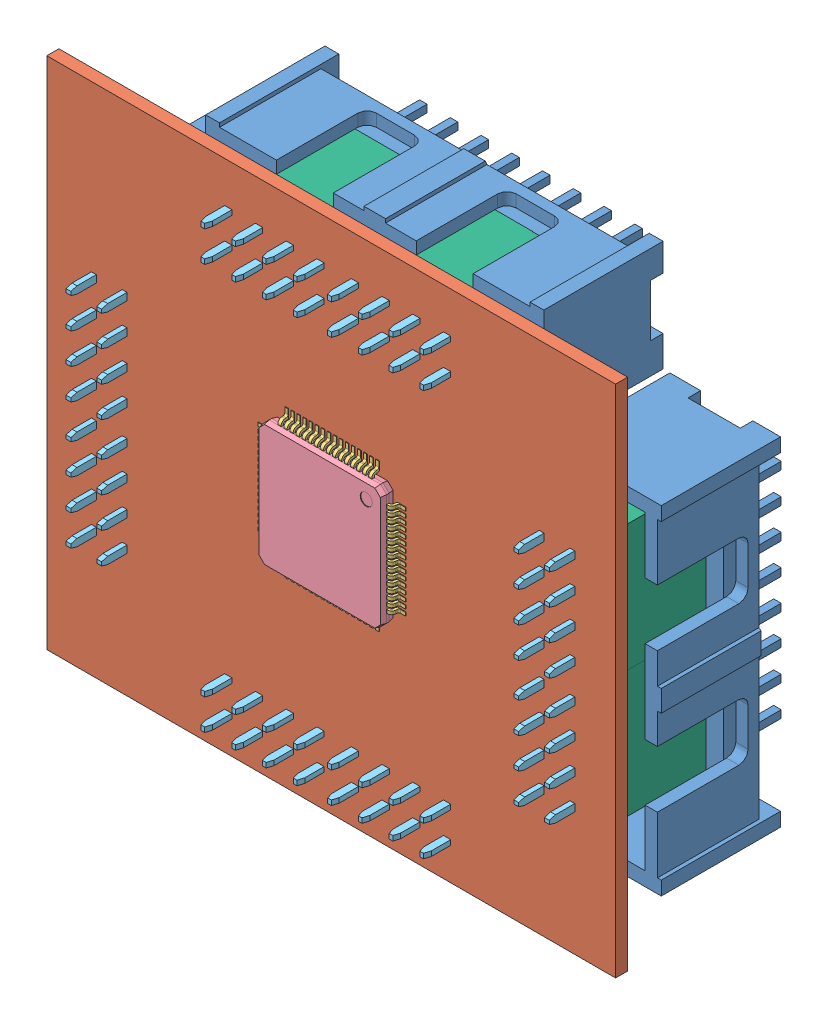
SolidWorks assembly Pic32Board-Chip-And-Support, configuration Défaut. Lengths in mm.
Overall size (47.77 43.45 18).
157 component instances, 6 part files, 4 mates.
Components (placement in the parent):
- Pic32Board-Support-1: Pic32Board-Support [Défaut] at (-7.1576 -16.2986 18.8481) size (46.79 42.79 12.9)
  - HE10-16Way-1: HE10-16Way [Default] at (-6.8205 -0.3878 34.3917) size (27.94 9.14 12.9)
  - HE10-16Way-3: HE10-16Way [Default] at (-6.8205 33.2562 34.3917) x (-1 0 0) z (0 0 1) size (27.94 9.14 12.9)
  - HE10-16Way-4: HE10-16Way [Default] at (12.2815 14.7142 34.3917) x (0 1 0) z (0 0 1) size (27.94 9.14 12.9)
  - HE10-16Way-5: HE10-16Way [Default] at (-25.3625 14.7142 34.3917) x (0 -1 0) z (0 0 1) size (27.94 9.14 12.9)
- Pic32Board-1: Pic32Board [Défaut] at (-20.8201 0.0031 8.7398) x (-1 0 0) z (0 0 1) size (47 42.5 11.6)
  - Pic32Board-1: Pic32Board [Défaut] at (-29.7416 -22.193 46.5) size (47 42.5 1)
  - User Library-TQFP64-2-1: User Library-TQFP64-2 [Default] at (-6.3416 -0.843 48.025) x (1 0 0) z (0 -1 0) size (12.2 1.2 12.2)
    - User Library-TQFP64-2_Leg x0-27 y0-575 z1-0-1: User Library-TQFP64-2_Leg x0-27 y0-575 z1-0 [Default] at (-5.1 0 -1.25) x (0 0 1) z (-1 0 0) size (0.27 0.78 1)
    - User Library-TQFP64-2_Leg x0-27 y0-575 z1-0-2: User Library-TQFP64-2_Leg x0-27 y0-575 z1-0 [Default] at (-2.75 0 -5.1001) x (-1 0 0) z (0 0 -1) size (0.27 0.78 1)
    - User Library-TQFP64-2_Leg x0-27 y0-575 z1-0-3: User Library-TQFP64-2_Leg x0-27 y0-575 z1-0 [Default] at (-5.1 0 2.25) x (0 0 1) z (-1 0 0) size (0.27 0.78 1)
    - User Library-TQFP64-2_Leg x0-27 y0-575 z1-0-4: User Library-TQFP64-2_Leg x0-27 y0-575 z1-0 [Default] at (5.1 0 -3.25) x (0 0 -1) z (1 0 0) size (0.27 0.78 1)
    - User Library-TQFP64-2_Leg x0-27 y0-575 z1-0-5: User Library-TQFP64-2_Leg x0-27 y0-575 z1-0 [Default] at (-1.25 0 5.1001) size (0.27 0.78 1)
    - User Library-TQFP64-2_Leg x0-27 y0-575 z1-0-6: User Library-TQFP64-2_Leg x0-27 y0-575 z1-0 [Default] at (2.75 0 5.1001) size (0.27 0.78 1)
    - User Library-TQFP64-2_Leg x0-27 y0-575 z1-0-7: User Library-TQFP64-2_Leg x0-27 y0-575 z1-0 [Default] at (2.25 0 5.1001) size (0.27 0.78 1)
    - User Library-TQFP64-2_Leg x0-27 y0-575 z1-0-8: User Library-TQFP64-2_Leg x0-27 y0-575 z1-0 [Default] at (5.1 0 -0.25) x (0 0 -1) z (1 0 0) size (0.27 0.78 1)
    - User Library-TQFP64-2_Leg x0-27 y0-575 z1-0-9: User Library-TQFP64-2_Leg x0-27 y0-575 z1-0 [Default] at (-5.1 0 -0.75) x (0 0 1) z (-1 0 0) size (0.27 0.78 1)
    - User Library-TQFP64-2_Leg x0-27 y0-575 z1-0-10: User Library-TQFP64-2_Leg x0-27 y0-575 z1-0 [Default] at (2.25 0 -5.1001) x (-1 0 0) z (0 0 -1) size (0.27 0.78 1)
    - User Library-TQFP64-2_Leg x0-27 y0-575 z1-0-11: User Library-TQFP64-2_Leg x0-27 y0-575 z1-0 [Default] at (5.1 0 0.75) x (0 0 -1) z (1 0 0) size (0.27 0.78 1)
    - User Library-TQFP64-2_Leg x0-27 y0-575 z1-0-12: User Library-TQFP64-2_Leg x0-27 y0-575 z1-0 [Default] at (-0.25 0 -5.1001) x (-1 0 0) z (0 0 -1) size (0.27 0.78 1)
    - User Library-TQFP64-2_Leg x0-27 y0-575 z1-0-13: User Library-TQFP64-2_Leg x0-27 y0-575 z1-0 [Default] at (5.1 0 0.25) x (0 0 -1) z (1 0 0) size (0.27 0.78 1)
    - User Library-TQFP64-2_Leg x0-27 y0-575 z1-0-14: User Library-TQFP64-2_Leg x0-27 y0-575 z1-0 [Default] at (1.75 0 5.1001) size (0.27 0.78 1)
    - User Library-TQFP64-2_Leg x0-27 y0-575 z1-0-15: User Library-TQFP64-2_Leg x0-27 y0-575 z1-0 [Default] at (-1.25 0 -5.1001) x (-1 0 0) z (0 0 -1) size (0.27 0.78 1)
    - User Library-TQFP64-2_Leg x0-27 y0-575 z1-0-16: User Library-TQFP64-2_Leg x0-27 y0-575 z1-0 [Default] at (-5.1 0 1.75) x (0 0 1) z (-1 0 0) size (0.27 0.78 1)
    - User Library-TQFP64-2_Leg x0-27 y0-575 z1-0-17: User Library-TQFP64-2_Leg x0-27 y0-575 z1-0 [Default] at (3.25 0 5.1001) size (0.27 0.78 1)
    - User Library-TQFP64-2_Leg x0-27 y0-575 z1-0-18: User Library-TQFP64-2_Leg x0-27 y0-575 z1-0 [Default] at (2.75 0 -5.1001) x (-1 0 0) z (0 0 -1) size (0.27 0.78 1)
    - User Library-TQFP64-2_Leg x0-27 y0-575 z1-0-19: User Library-TQFP64-2_Leg x0-27 y0-575 z1-0 [Default] at (5.1 0 2.25) x (0 0 -1) z (1 0 0) size (0.27 0.78 1)
    - User Library-TQFP64-2_Leg x0-27 y0-575 z1-0-20: User Library-TQFP64-2_Leg x0-27 y0-575 z1-0 [Default] at (-3.25 0 -5.1001) x (-1 0 0) z (0 0 -1) size (0.27 0.78 1)
    - User Library-TQFP64-2_Leg x0-27 y0-575 z1-0-21: User Library-TQFP64-2_Leg x0-27 y0-575 z1-0 [Default] at (-3.75 0 5.1001) size (0.27 0.78 1)
    - User Library-TQFP64-2_Leg x0-27 y0-575 z1-0-22: User Library-TQFP64-2_Leg x0-27 y0-575 z1-0 [Default] at (-3.25 0 5.1001) size (0.27 0.78 1)
    - User Library-TQFP64-2_Leg x0-27 y0-575 z1-0-23: User Library-TQFP64-2_Leg x0-27 y0-575 z1-0 [Default] at (3.75 0 5.1001) size (0.27 0.78 1)
    - User Library-TQFP64-2_Leg x0-27 y0-575 z1-0-24: User Library-TQFP64-2_Leg x0-27 y0-575 z1-0 [Default] at (-5.1 0 0.25) x (0 0 1) z (-1 0 0) size (0.27 0.78 1)
    - User Library-TQFP64-2_Leg x0-27 y0-575 z1-0-25: User Library-TQFP64-2_Leg x0-27 y0-575 z1-0 [Default] at (5.1 0 3.25) x (0 0 -1) z (1 0 0) size (0.27 0.78 1)
    - User Library-TQFP64-2_Leg x0-27 y0-575 z1-0-26: User Library-TQFP64-2_Leg x0-27 y0-575 z1-0 [Default] at (-5.1 0 0.75) x (0 0 1) z (-1 0 0) size (0.27 0.78 1)
    - User Library-TQFP64-2_Leg x0-27 y0-575 z1-0-27: User Library-TQFP64-2_Leg x0-27 y0-575 z1-0 [Default] at (0.75 0 -5.1001) x (-1 0 0) z (0 0 -1) size (0.27 0.78 1)
    - User Library-TQFP64-2_Leg x0-27 y0-575 z1-0-28: User Library-TQFP64-2_Leg x0-27 y0-575 z1-0 [Default] at (5.1 0 1.75) x (0 0 -1) z (1 0 0) size (0.27 0.78 1)
    - User Library-TQFP64-2_Leg x0-27 y0-575 z1-0-29: User Library-TQFP64-2_Leg x0-27 y0-575 z1-0 [Default] at (-5.1 0 -3.75) x (0 0 1) z (-1 0 0) size (0.27 0.78 1)
    - User Library-TQFP64-2_Leg x0-27 y0-575 z1-0-30: User Library-TQFP64-2_Leg x0-27 y0-575 z1-0 [Default] at (5.1 0 -0.75) x (0 0 -1) z (1 0 0) size (0.27 0.78 1)
    - User Library-TQFP64-2_Leg x0-27 y0-575 z1-0-31: User Library-TQFP64-2_Leg x0-27 y0-575 z1-0 [Default] at (5.1 0 3.75) x (0 0 -1) z (1 0 0) size (0.27 0.78 1)
    - User Library-TQFP64-2_Leg x0-27 y0-575 z1-0-32: User Library-TQFP64-2_Leg x0-27 y0-575 z1-0 [Default] at (-2.25 0 5.1001) size (0.27 0.78 1)
    - User Library-TQFP64-2_Leg x0-27 y0-575 z1-0-33: User Library-TQFP64-2_Leg x0-27 y0-575 z1-0 [Default] at (-5.1 0 -3.25) x (0 0 1) z (-1 0 0) size (0.27 0.78 1)
    - User Library-TQFP64-2_Leg x0-27 y0-575 z1-0-34: User Library-TQFP64-2_Leg x0-27 y0-575 z1-0 [Default] at (-5.1 0 2.75) x (0 0 1) z (-1 0 0) size (0.27 0.78 1)
    - User Library-TQFP64-2_Leg x0-27 y0-575 z1-0-35: User Library-TQFP64-2_Leg x0-27 y0-575 z1-0 [Default] at (-5.1 0 3.75) x (0 0 1) z (-1 0 0) size (0.27 0.78 1)
    - User Library-TQFP64-2_Leg x0-27 y0-575 z1-0-36: User Library-TQFP64-2_Leg x0-27 y0-575 z1-0 [Default] at (1.25 0 -5.1001) x (-1 0 0) z (0 0 -1) size (0.27 0.78 1)
    - User Library-TQFP64-2_Leg x0-27 y0-575 z1-0-37: User Library-TQFP64-2_Leg x0-27 y0-575 z1-0 [Default] at (1.25 0 5.1001) size (0.27 0.78 1)
    - User Library-TQFP64-2_Leg x0-27 y0-575 z1-0-38: User Library-TQFP64-2_Leg x0-27 y0-575 z1-0 [Default] at (5.1 0 1.25) x (0 0 -1) z (1 0 0) size (0.27 0.78 1)
    - User Library-TQFP64-2_Leg x0-27 y0-575 z1-0-39: User Library-TQFP64-2_Leg x0-27 y0-575 z1-0 [Default] at (0.75 0 5.1001) size (0.27 0.78 1)
    - User Library-TQFP64-2_Leg x0-27 y0-575 z1-0-40: User Library-TQFP64-2_Leg x0-27 y0-575 z1-0 [Default] at (3.25 0 -5.1001) x (-1 0 0) z (0 0 -1) size (0.27 0.78 1)
    - User Library-TQFP64-2_Leg x0-27 y0-575 z1-0-41: User Library-TQFP64-2_Leg x0-27 y0-575 z1-0 [Default] at (-2.75 0 5.1001) size (0.27 0.78 1)
    - User Library-TQFP64-2_Leg x0-27 y0-575 z1-0-42: User Library-TQFP64-2_Leg x0-27 y0-575 z1-0 [Default] at (3.75 0 -5.1001) x (-1 0 0) z (0 0 -1) size (0.27 0.78 1)
    - User Library-TQFP64-2_Leg x0-27 y0-575 z1-0-43: User Library-TQFP64-2_Leg x0-27 y0-575 z1-0 [Default] at (1.75 0 -5.1001) x (-1 0 0) z (0 0 -1) size (0.27 0.78 1)
    - User Library-TQFP64-2_Leg x0-27 y0-575 z1-0-44: User Library-TQFP64-2_Leg x0-27 y0-575 z1-0 [Default] at (-5.1 0 -2.75) x (0 0 1) z (-1 0 0) size (0.27 0.78 1)
    - User Library-TQFP64-2_Leg x0-27 y0-575 z1-0-45: User Library-TQFP64-2_Leg x0-27 y0-575 z1-0 [Default] at (5.1 0 -2.25) x (0 0 -1) z (1 0 0) size (0.27 0.78 1)
    - User Library-TQFP64-2_Leg x0-27 y0-575 z1-0-46: User Library-TQFP64-2_Leg x0-27 y0-575 z1-0 [Default] at (-2.25 0 -5.1001) x (-1 0 0) z (0 0 -1) size (0.27 0.78 1)
    - User Library-TQFP64-2_Leg x0-27 y0-575 z1-0-47: User Library-TQFP64-2_Leg x0-27 y0-575 z1-0 [Default] at (-5.1 0 1.25) x (0 0 1) z (-1 0 0) size (0.27 0.78 1)
    - User Library-TQFP64-2_Leg x0-27 y0-575 z1-0-48: User Library-TQFP64-2_Leg x0-27 y0-575 z1-0 [Default] at (5.1 0 -3.75) x (0 0 -1) z (1 0 0) size (0.27 0.78 1)
    - User Library-TQFP64-2_Leg x0-27 y0-575 z1-0-49: User Library-TQFP64-2_Leg x0-27 y0-575 z1-0 [Default] at (0.25 0 -5.1001) x (-1 0 0) z (0 0 -1) size (0.27 0.78 1)
    - User Library-TQFP64-2_Leg x0-27 y0-575 z1-0-50: User Library-TQFP64-2_Leg x0-27 y0-575 z1-0 [Default] at (-3.75 0 -5.1001) x (-1 0 0) z (0 0 -1) size (0.27 0.78 1)
    - User Library-TQFP64-2_Leg x0-27 y0-575 z1-0-51: User Library-TQFP64-2_Leg x0-27 y0-575 z1-0 [Default] at (-5.1 0 -0.25) x (0 0 1) z (-1 0 0) size (0.27 0.78 1)
    - User Library-TQFP64-2_Leg x0-27 y0-575 z1-0-52: User Library-TQFP64-2_Leg x0-27 y0-575 z1-0 [Default] at (-0.75 0 5.1001) size (0.27 0.78 1)
    - User Library-TQFP64-2_Leg x0-27 y0-575 z1-0-53: User Library-TQFP64-2_Leg x0-27 y0-575 z1-0 [Default] at (5.1 0 -1.75) x (0 0 -1) z (1 0 0) size (0.27 0.78 1)
    - User Library-TQFP64-2_Leg x0-27 y0-575 z1-0-54: User Library-TQFP64-2_Leg x0-27 y0-575 z1-0 [Default] at (-5.1 0 -2.25) x (0 0 1) z (-1 0 0) size (0.27 0.78 1)
    - User Library-TQFP64-2_Leg x0-27 y0-575 z1-0-55: User Library-TQFP64-2_Leg x0-27 y0-575 z1-0 [Default] at (-0.75 0 -5.1001) x (-1 0 0) z (0 0 -1) size (0.27 0.78 1)
    - User Library-TQFP64-2_Leg x0-27 y0-575 z1-0-56: User Library-TQFP64-2_Leg x0-27 y0-575 z1-0 [Default] at (-5.1 0 3.25) x (0 0 1) z (-1 0 0) size (0.27 0.78 1)
    - User Library-TQFP64-2_Body x10-2 y10-2 z1-05-1: User Library-TQFP64-2_Body x10-2 y10-2 z1-05 [Default] at origin size (10.2 1.05 10.2)
    - User Library-TQFP64-2_Leg x0-27 y0-575 z1-0-57: User Library-TQFP64-2_Leg x0-27 y0-575 z1-0 [Default] at (0.25 0 5.1001) size (0.27 0.78 1)
    - User Library-TQFP64-2_Leg x0-27 y0-575 z1-0-58: User Library-TQFP64-2_Leg x0-27 y0-575 z1-0 [Default] at (5.1 0 2.75) x (0 0 -1) z (1 0 0) size (0.27 0.78 1)
    - User Library-TQFP64-2_Leg x0-27 y0-575 z1-0-59: User Library-TQFP64-2_Leg x0-27 y0-575 z1-0 [Default] at (-1.75 0 -5.1001) x (-1 0 0) z (0 0 -1) size (0.27 0.78 1)
    - User Library-TQFP64-2_Leg x0-27 y0-575 z1-0-60: User Library-TQFP64-2_Leg x0-27 y0-575 z1-0 [Default] at (-5.1 0 -1.75) x (0 0 1) z (-1 0 0) size (0.27 0.78 1)
    - User Library-TQFP64-2_Leg x0-27 y0-575 z1-0-61: User Library-TQFP64-2_Leg x0-27 y0-575 z1-0 [Default] at (-0.25 0 5.1001) size (0.27 0.78 1)
    - User Library-TQFP64-2_Leg x0-27 y0-575 z1-0-62: User Library-TQFP64-2_Leg x0-27 y0-575 z1-0 [Default] at (-1.75 0 5.1001) size (0.27 0.78 1)
    - User Library-TQFP64-2_Leg x0-27 y0-575 z1-0-63: User Library-TQFP64-2_Leg x0-27 y0-575 z1-0 [Default] at (5.1 0 -2.75) x (0 0 -1) z (1 0 0) size (0.27 0.78 1)
    - User Library-TQFP64-2_Leg x0-27 y0-575 z1-0-64: User Library-TQFP64-2_Leg x0-27 y0-575 z1-0 [Default] at (5.1 0 -1.25) x (0 0 -1) z (1 0 0) size (0.27 0.78 1)
  - HE10-16Way-Female-1: HE10-16Way-Female [Défaut] at (-8.4334 -17.4128 55.4002) x (1 0 0) z (0 0 -1) size (20.92 5.68 11.6)
    - User Library-MULTICOMP 2214S-08SG-85-1: User Library-MULTICOMP 2214S-08SG-85 [Default] at (-3.5782 -0.0598 8.9002) size (10.46 5.68 11.6)
      - User Library-MULTICOMP 2214S-08SG-85_contact-1: User Library-MULTICOMP 2214S-08SG-85_contact [Default] at (-3.81 -1.07 0.9) x (1 0 0) z (0 -1 0) size (2 10 0.4)
      - User Library-MULTICOMP 2214S-08SG-85_contact-2: User Library-MULTICOMP 2214S-08SG-85_contact [Default] at (-3.81 1.47 0.9) x (1 0 0) z (0 -1 0) size (2 10 0.4)
      - User Library-MULTICOMP 2214S-08SG-85_contact-3: User Library-MULTICOMP 2214S-08SG-85_contact [Default] at (-1.27 -1.07 0.9) x (1 0 0) z (0 -1 0) size (2 10 0.4)
      - User Library-MULTICOMP 2214S-08SG-85_contact-4: User Library-MULTICOMP 2214S-08SG-85_contact [Default] at (-1.27 1.47 0.9) x (1 0 0) z (0 -1 0) size (2 10 0.4)
      - User Library-MULTICOMP 2214S-08SG-85_contact-5: User Library-MULTICOMP 2214S-08SG-85_contact [Default] at (1.27 1.47 0.9) x (1 0 0) z (0 -1 0) size (2 10 0.4)
      - User Library-MULTICOMP 2214S-08SG-85_contact-6: User Library-MULTICOMP 2214S-08SG-85_contact [Default] at (1.27 -1.07 0.9) x (1 0 0) z (0 -1 0) size (2 10 0.4)
      - User Library-MULTICOMP 2214S-08SG-85_contact-7: User Library-MULTICOMP 2214S-08SG-85_contact [Default] at (3.81 -1.47 0.9) x (-1 0 0) z (0 1 0) size (2 10 0.4)
      - User Library-MULTICOMP 2214S-08SG-85_contact-8: User Library-MULTICOMP 2214S-08SG-85_contact [Default] at (3.81 1.07 0.9) x (-1 0 0) z (0 1 0) size (2 10 0.4)
      - User Library-MULTICOMP 2214S-08SG-85_housing-1: User Library-MULTICOMP 2214S-08SG-85_housing [Default] at origin size (10.46 5.68 8.5)
    - User Library-MULTICOMP 2214S-08SG-85-2: User Library-MULTICOMP 2214S-08SG-85 [Default] at (6.8818 -0.0598 8.9002) size (10.46 5.68 11.6)
      - User Library-MULTICOMP 2214S-08SG-85_contact-1: User Library-MULTICOMP 2214S-08SG-85_contact [Default] at (-3.81 -1.07 0.9) x (1 0 0) z (0 -1 0) size (2 10 0.4)
      - User Library-MULTICOMP 2214S-08SG-85_contact-2: User Library-MULTICOMP 2214S-08SG-85_contact [Default] at (-3.81 1.47 0.9) x (1 0 0) z (0 -1 0) size (2 10 0.4)
      - User Library-MULTICOMP 2214S-08SG-85_contact-3: User Library-MULTICOMP 2214S-08SG-85_contact [Default] at (-1.27 -1.07 0.9) x (1 0 0) z (0 -1 0) size (2 10 0.4)
      - User Library-MULTICOMP 2214S-08SG-85_contact-4: User Library-MULTICOMP 2214S-08SG-85_contact [Default] at (-1.27 1.47 0.9) x (1 0 0) z (0 -1 0) size (2 10 0.4)
      - User Library-MULTICOMP 2214S-08SG-85_contact-5: User Library-MULTICOMP 2214S-08SG-85_contact [Default] at (1.27 1.47 0.9) x (1 0 0) z (0 -1 0) size (2 10 0.4)
      - User Library-MULTICOMP 2214S-08SG-85_contact-6: User Library-MULTICOMP 2214S-08SG-85_contact [Default] at (1.27 -1.07 0.9) x (1 0 0) z (0 -1 0) size (2 10 0.4)
      - User Library-MULTICOMP 2214S-08SG-85_contact-7: User Library-MULTICOMP 2214S-08SG-85_contact [Default] at (3.81 -1.47 0.9) x (-1 0 0) z (0 1 0) size (2 10 0.4)
      - User Library-MULTICOMP 2214S-08SG-85_contact-8: User Library-MULTICOMP 2214S-08SG-85_contact [Default] at (3.81 1.07 0.9) x (-1 0 0) z (0 1 0) size (2 10 0.4)
      - User Library-MULTICOMP 2214S-08SG-85_housing-1: User Library-MULTICOMP 2214S-08SG-85_housing [Default] at origin size (10.46 5.68 8.5)
  - HE10-16Way-Female-2: HE10-16Way-Female [Défaut] at (-8.4334 16.0872 55.4002) x (1 0 0) z (0 0 -1) size (20.92 5.68 11.6)
    - User Library-MULTICOMP 2214S-08SG-85-1: User Library-MULTICOMP 2214S-08SG-85 [Default] at (-3.5782 -0.0598 8.9002) size (10.46 5.68 11.6)
      - User Library-MULTICOMP 2214S-08SG-85_contact-1: User Library-MULTICOMP 2214S-08SG-85_contact [Default] at (-3.81 -1.07 0.9) x (1 0 0) z (0 -1 0) size (2 10 0.4)
      - User Library-MULTICOMP 2214S-08SG-85_contact-2: User Library-MULTICOMP 2214S-08SG-85_contact [Default] at (-3.81 1.47 0.9) x (1 0 0) z (0 -1 0) size (2 10 0.4)
      - User Library-MULTICOMP 2214S-08SG-85_contact-3: User Library-MULTICOMP 2214S-08SG-85_contact [Default] at (-1.27 -1.07 0.9) x (1 0 0) z (0 -1 0) size (2 10 0.4)
      - User Library-MULTICOMP 2214S-08SG-85_contact-4: User Library-MULTICOMP 2214S-08SG-85_contact [Default] at (-1.27 1.47 0.9) x (1 0 0) z (0 -1 0) size (2 10 0.4)
      - User Library-MULTICOMP 2214S-08SG-85_contact-5: User Library-MULTICOMP 2214S-08SG-85_contact [Default] at (1.27 1.47 0.9) x (1 0 0) z (0 -1 0) size (2 10 0.4)
      - User Library-MULTICOMP 2214S-08SG-85_contact-6: User Library-MULTICOMP 2214S-08SG-85_contact [Default] at (1.27 -1.07 0.9) x (1 0 0) z (0 -1 0) size (2 10 0.4)
      - User Library-MULTICOMP 2214S-08SG-85_contact-7: User Library-MULTICOMP 2214S-08SG-85_contact [Default] at (3.81 -1.47 0.9) x (-1 0 0) z (0 1 0) size (2 10 0.4)
      - User Library-MULTICOMP 2214S-08SG-85_contact-8: User Library-MULTICOMP 2214S-08SG-85_contact [Default] at (3.81 1.07 0.9) x (-1 0 0) z (0 1 0) size (2 10 0.4)
      - User Library-MULTICOMP 2214S-08SG-85_housing-1: User Library-MULTICOMP 2214S-08SG-85_housing [Default] at origin size (10.46 5.68 8.5)
    - User Library-MULTICOMP 2214S-08SG-85-2: User Library-MULTICOMP 2214S-08SG-85 [Default] at (6.8818 -0.0598 8.9002) size (10.46 5.68 11.6)
      - User Library-MULTICOMP 2214S-08SG-85_contact-1: User Library-MULTICOMP 2214S-08SG-85_contact [Default] at (-3.81 -1.07 0.9) x (1 0 0) z (0 -1 0) size (2 10 0.4)
      - User Library-MULTICOMP 2214S-08SG-85_contact-2: User Library-MULTICOMP 2214S-08SG-85_contact [Default] at (-3.81 1.47 0.9) x (1 0 0) z (0 -1 0) size (2 10 0.4)
      - User Library-MULTICOMP 2214S-08SG-85_contact-3: User Library-MULTICOMP 2214S-08SG-85_contact [Default] at (-1.27 -1.07 0.9) x (1 0 0) z (0 -1 0) size (2 10 0.4)
      - User Library-MULTICOMP 2214S-08SG-85_contact-4: User Library-MULTICOMP 2214S-08SG-85_contact [Default] at (-1.27 1.47 0.9) x (1 0 0) z (0 -1 0) size (2 10 0.4)
      - User Library-MULTICOMP 2214S-08SG-85_contact-5: User Library-MULTICOMP 2214S-08SG-85_contact [Default] at (1.27 1.47 0.9) x (1 0 0) z (0 -1 0) size (2 10 0.4)
      - User Library-MULTICOMP 2214S-08SG-85_contact-6: User Library-MULTICOMP 2214S-08SG-85_contact [Default] at (1.27 -1.07 0.9) x (1 0 0) z (0 -1 0) size (2 10 0.4)
      - User Library-MULTICOMP 2214S-08SG-85_contact-7: User Library-MULTICOMP 2214S-08SG-85_contact [Default] at (3.81 -1.47 0.9) x (-1 0 0) z (0 1 0) size (2 10 0.4)
      - User Library-MULTICOMP 2214S-08SG-85_contact-8: User Library-MULTICOMP 2214S-08SG-85_contact [Default] at (3.81 1.07 0.9) x (-1 0 0) z (0 1 0) size (2 10 0.4)
      - User Library-MULTICOMP 2214S-08SG-85_housing-1: User Library-MULTICOMP 2214S-08SG-85_housing [Default] at origin size (10.46 5.68 8.5)
  - HE10-16Way-Female-3: HE10-16Way-Female [Défaut] at (-24.9614 2.4188 55.4002) x (0 -1 0) z (0 0 -1) size (20.92 5.68 11.6)
    - User Library-MULTICOMP 2214S-08SG-85-1: User Library-MULTICOMP 2214S-08SG-85 [Default] at (-3.5782 -0.0598 8.9002) size (10.46 5.68 11.6)
      - User Library-MULTICOMP 2214S-08SG-85_contact-1: User Library-MULTICOMP 2214S-08SG-85_contact [Default] at (-3.81 -1.07 0.9) x (1 0 0) z (0 -1 0) size (2 10 0.4)
      - User Library-MULTICOMP 2214S-08SG-85_contact-2: User Library-MULTICOMP 2214S-08SG-85_contact [Default] at (-3.81 1.47 0.9) x (1 0 0) z (0 -1 0) size (2 10 0.4)
      - User Library-MULTICOMP 2214S-08SG-85_contact-3: User Library-MULTICOMP 2214S-08SG-85_contact [Default] at (-1.27 -1.07 0.9) x (1 0 0) z (0 -1 0) size (2 10 0.4)
      - User Library-MULTICOMP 2214S-08SG-85_contact-4: User Library-MULTICOMP 2214S-08SG-85_contact [Default] at (-1.27 1.47 0.9) x (1 0 0) z (0 -1 0) size (2 10 0.4)
      - User Library-MULTICOMP 2214S-08SG-85_contact-5: User Library-MULTICOMP 2214S-08SG-85_contact [Default] at (1.27 1.47 0.9) x (1 0 0) z (0 -1 0) size (2 10 0.4)
      - User Library-MULTICOMP 2214S-08SG-85_contact-6: User Library-MULTICOMP 2214S-08SG-85_contact [Default] at (1.27 -1.07 0.9) x (1 0 0) z (0 -1 0) size (2 10 0.4)
      - User Library-MULTICOMP 2214S-08SG-85_contact-7: User Library-MULTICOMP 2214S-08SG-85_contact [Default] at (3.81 -1.47 0.9) x (-1 0 0) z (0 1 0) size (2 10 0.4)
      - User Library-MULTICOMP 2214S-08SG-85_contact-8: User Library-MULTICOMP 2214S-08SG-85_contact [Default] at (3.81 1.07 0.9) x (-1 0 0) z (0 1 0) size (2 10 0.4)
      - User Library-MULTICOMP 2214S-08SG-85_housing-1: User Library-MULTICOMP 2214S-08SG-85_housing [Default] at origin size (10.46 5.68 8.5)
    - User Library-MULTICOMP 2214S-08SG-85-2: User Library-MULTICOMP 2214S-08SG-85 [Default] at (6.8818 -0.0598 8.9002) size (10.46 5.68 11.6)
      - User Library-MULTICOMP 2214S-08SG-85_contact-1: User Library-MULTICOMP 2214S-08SG-85_contact [Default] at (-3.81 -1.07 0.9) x (1 0 0) z (0 -1 0) size (2 10 0.4)
      - User Library-MULTICOMP 2214S-08SG-85_contact-2: User Library-MULTICOMP 2214S-08SG-85_contact [Default] at (-3.81 1.47 0.9) x (1 0 0) z (0 -1 0) size (2 10 0.4)
      - User Library-MULTICOMP 2214S-08SG-85_contact-3: User Library-MULTICOMP 2214S-08SG-85_contact [Default] at (-1.27 -1.07 0.9) x (1 0 0) z (0 -1 0) size (2 10 0.4)
      - User Library-MULTICOMP 2214S-08SG-85_contact-4: User Library-MULTICOMP 2214S-08SG-85_contact [Default] at (-1.27 1.47 0.9) x (1 0 0) z (0 -1 0) size (2 10 0.4)
      - User Library-MULTICOMP 2214S-08SG-85_contact-5: User Library-MULTICOMP 2214S-08SG-85_contact [Default] at (1.27 1.47 0.9) x (1 0 0) z (0 -1 0) size (2 10 0.4)
      - User Library-MULTICOMP 2214S-08SG-85_contact-6: User Library-MULTICOMP 2214S-08SG-85_contact [Default] at (1.27 -1.07 0.9) x (1 0 0) z (0 -1 0) size (2 10 0.4)
      - User Library-MULTICOMP 2214S-08SG-85_contact-7: User Library-MULTICOMP 2214S-08SG-85_contact [Default] at (3.81 -1.47 0.9) x (-1 0 0) z (0 1 0) size (2 10 0.4)
      - User Library-MULTICOMP 2214S-08SG-85_contact-8: User Library-MULTICOMP 2214S-08SG-85_contact [Default] at (3.81 1.07 0.9) x (-1 0 0) z (0 1 0) size (2 10 0.4)
      - User Library-MULTICOMP 2214S-08SG-85_housing-1: User Library-MULTICOMP 2214S-08SG-85_housing [Default] at origin size (10.46 5.68 8.5)
  - HE10-16Way-Female-4: HE10-16Way-Female [Défaut] at (12.0386 2.4188 55.4002) x (0 -1 0) z (0 0 -1) size (20.92 5.68 11.6)
    - User Library-MULTICOMP 2214S-08SG-85-1: User Library-MULTICOMP 2214S-08SG-85 [Default] at (-3.5782 -0.0598 8.9002) size (10.46 5.68 11.6)
      - User Library-MULTICOMP 2214S-08SG-85_contact-1: User Library-MULTICOMP 2214S-08SG-85_contact [Default] at (-3.81 -1.07 0.9) x (1 0 0) z (0 -1 0) size (2 10 0.4)
      - User Library-MULTICOMP 2214S-08SG-85_contact-2: User Library-MULTICOMP 2214S-08SG-85_contact [Default] at (-3.81 1.47 0.9) x (1 0 0) z (0 -1 0) size (2 10 0.4)
      - User Library-MULTICOMP 2214S-08SG-85_contact-3: User Library-MULTICOMP 2214S-08SG-85_contact [Default] at (-1.27 -1.07 0.9) x (1 0 0) z (0 -1 0) size (2 10 0.4)
      - User Library-MULTICOMP 2214S-08SG-85_contact-4: User Library-MULTICOMP 2214S-08SG-85_contact [Default] at (-1.27 1.47 0.9) x (1 0 0) z (0 -1 0) size (2 10 0.4)
      - User Library-MULTICOMP 2214S-08SG-85_contact-5: User Library-MULTICOMP 2214S-08SG-85_contact [Default] at (1.27 1.47 0.9) x (1 0 0) z (0 -1 0) size (2 10 0.4)
      - User Library-MULTICOMP 2214S-08SG-85_contact-6: User Library-MULTICOMP 2214S-08SG-85_contact [Default] at (1.27 -1.07 0.9) x (1 0 0) z (0 -1 0) size (2 10 0.4)
      - User Library-MULTICOMP 2214S-08SG-85_contact-7: User Library-MULTICOMP 2214S-08SG-85_contact [Default] at (3.81 -1.47 0.9) x (-1 0 0) z (0 1 0) size (2 10 0.4)
      - User Library-MULTICOMP 2214S-08SG-85_contact-8: User Library-MULTICOMP 2214S-08SG-85_contact [Default] at (3.81 1.07 0.9) x (-1 0 0) z (0 1 0) size (2 10 0.4)
      - User Library-MULTICOMP 2214S-08SG-85_housing-1: User Library-MULTICOMP 2214S-08SG-85_housing [Default] at origin size (10.46 5.68 8.5)
    - User Library-MULTICOMP 2214S-08SG-85-2: User Library-MULTICOMP 2214S-08SG-85 [Default] at (6.8818 -0.0598 8.9002) size (10.46 5.68 11.6)
      - User Library-MULTICOMP 2214S-08SG-85_contact-1: User Library-MULTICOMP 2214S-08SG-85_contact [Default] at (-3.81 -1.07 0.9) x (1 0 0) z (0 -1 0) size (2 10 0.4)
      - User Library-MULTICOMP 2214S-08SG-85_contact-2: User Library-MULTICOMP 2214S-08SG-85_contact [Default] at (-3.81 1.47 0.9) x (1 0 0) z (0 -1 0) size (2 10 0.4)
      - User Library-MULTICOMP 2214S-08SG-85_contact-3: User Library-MULTICOMP 2214S-08SG-85_contact [Default] at (-1.27 -1.07 0.9) x (1 0 0) z (0 -1 0) size (2 10 0.4)
      - User Library-MULTICOMP 2214S-08SG-85_contact-4: User Library-MULTICOMP 2214S-08SG-85_contact [Default] at (-1.27 1.47 0.9) x (1 0 0) z (0 -1 0) size (2 10 0.4)
      - User Library-MULTICOMP 2214S-08SG-85_contact-5: User Library-MULTICOMP 2214S-08SG-85_contact [Default] at (1.27 1.47 0.9) x (1 0 0) z (0 -1 0) size (2 10 0.4)
      - User Library-MULTICOMP 2214S-08SG-85_contact-6: User Library-MULTICOMP 2214S-08SG-85_contact [Default] at (1.27 -1.07 0.9) x (1 0 0) z (0 -1 0) size (2 10 0.4)
      - User Library-MULTICOMP 2214S-08SG-85_contact-7: User Library-MULTICOMP 2214S-08SG-85_contact [Default] at (3.81 -1.47 0.9) x (-1 0 0) z (0 1 0) size (2 10 0.4)
      - User Library-MULTICOMP 2214S-08SG-85_contact-8: User Library-MULTICOMP 2214S-08SG-85_contact [Default] at (3.81 1.07 0.9) x (-1 0 0) z (0 1 0) size (2 10 0.4)
      - User Library-MULTICOMP 2214S-08SG-85_housing-1: User Library-MULTICOMP 2214S-08SG-85_housing [Default] at origin size (10.46 5.68 8.5)
Mates (geometry in assembly coordinates):
- Distance1: distance = 2 mm anti-aligned: plane of Pic32Board-Support-1/HE10-16Way-1 through (-13.978 -16.6864 53.2398) normal (0 0 1); plane of Pic32Board-1/Pic32Board-1 through (8.9215 22.1961 55.2398) normal (0 0 -1)
- Parallèle2: parallel aligned: plane of Pic32Board-Support-1/HE10-16Way-3 through (-0.008 21.5296 53.2398) normal (0 1 0); plane of ? through (8.9215 22.1961 54.2398) normal (0 1 0)
- Coïncidente5: coincident anti-aligned: plane of Pic32Board-Support-1/HE10-16Way-3 through (-1.151 20.1961 53.2398) normal (0 -1 0); plane of ? through (-19.2685 20.1961 53.2398) normal (0 1 0)
- Coïncidente6: coincident anti-aligned: plane of Pic32Board-Support-1/HE10-16Way-5 through (-35.7585 11.2426 53.2398) normal (1 0 0); plane of ? through (-35.7585 4.4661 53.2398) normal (-1 0 0)
